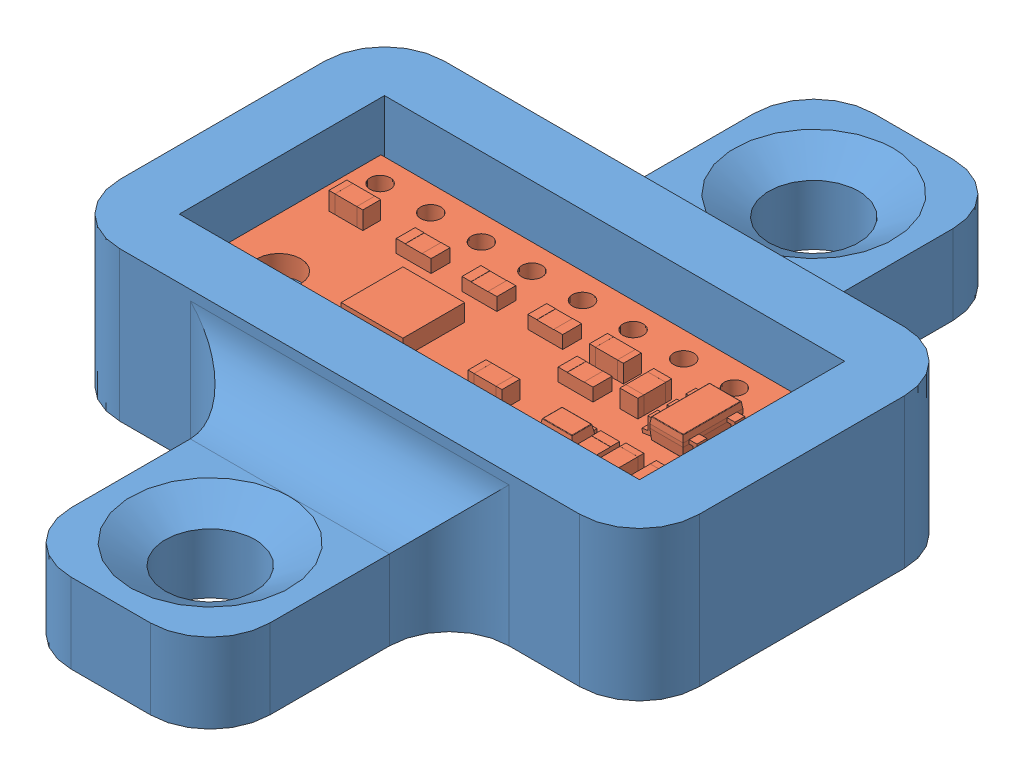
SolidWorks assembly Assem2, configuration Default. Lengths in mm.
Overall size (29.1 7.5 40.3).
2 component instances, 2 part files, 3 mates.
Components (placement in the parent):
- compassMount-1: compassMount [Default] at (0.8326 16.9055 38.181) size (29.1 7.5 40.3)
- compassIC_LSM303D-1: compassIC_LSM303D [Default] at (3.7926 20.9055 25.061) x (0 0 1) z (0 1 0) size (10.16 22.86 2.22)
Mates (geometry in assembly coordinates):
- Concentric1: concentric: circle of compassMount-1; circle of compassIC_LSM303D-1
- Coincident1: coincident: plane of compassMount-1 through (0.8326 20.9055 38.181) normal (0 1 0); plane of compassIC_LSM303D-1 through (3.7926 20.9055 25.061) normal (0 -1 0)
- Parallel1: parallel: plane of compassMount-1 through (26.9326 24.4055 24.881) normal (0 0 1); plane of compassIC_LSM303D-1 through (26.6526 21.9215 25.061) normal (0 0 -1)
